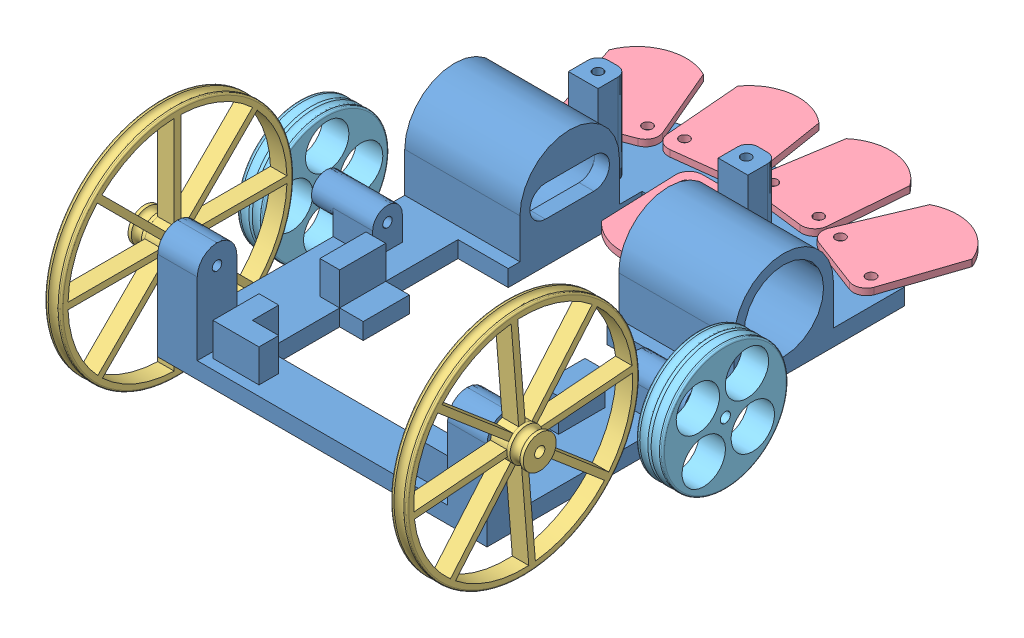
SolidWorks assembly LFR2, configuration Default. Lengths in mm.
Overall size (129.2 79.16 191.87).
11 component instances, 5 part files, 25 mates.
Components (placement in the parent):
- BODY3-1: BODY3 [Default] at origin size (113.2 33 138.84)
- BALL-1: BALL [Default] at (0 4.6 -27.733) x (1 0 0) z (0 0 -1) size (10 10 10)
- INTERMEDIATE65mm-1: INTERMEDIATE65mm [Default] at (50 27 94) x (0 0.080694 -0.996739) z (1 0 0) size (70.5 70.5 10)
- SENSOR-1: SENSOR [Default] at (-0.2782 5 -19.6543) size (24 2 32.42)
- SENSOR-2: SENSOR [Default] at (-36.4731 5 -24.2592) x (-0.934298 0 0.356493) z (-0.356493 0 -0.934298) size (24 2 32.42)
- SENSOR-3: SENSOR [Default] at (36.2225 5 -24.3544) x (-0.935229 0 -0.354044) z (0.354044 0 -0.935229) size (24 2 32.42)
- SENSOR-4: SENSOR [Default] at (12.3119 5 -30.2377) x (-0.992733 0 -0.120338) z (0.120338 0 -0.992733) size (24 2 32.42)
- SENSOR-5: SENSOR [Default] at (-12.3119 5 -30.2377) x (-0.992733 0 0.120338) z (-0.120338 0 -0.992733) size (24 2 32.42)
- INTERMEDIATE65mm-3: INTERMEDIATE65mm [Default] at (-50 27 94) x (0 0 1) z (-1 0 0) size (70.5 70.5 10)
- WHEEL-1: WHEEL [Default] at (-64.6 12.5 42.2315) x (0 -0.027962 -0.999609) z (1 0 0) size (38 38 8)
- WHEEL-2: WHEEL [Default] at (64.6 12.5 42.2315) x (0 0.618239 0.78599) z (-1 0 0) size (38 38 8)
Mates (geometry in assembly coordinates):
- Coincident1: coincident anti-aligned: plane of BODY3-1 through (0 5 71.3298) normal (0 1 0); plane of SENSOR-4 through (20.2538 5 -29.275) normal (0 -1 0)
- Coincident2: coincident anti-aligned: plane of BODY3-1 through (0 5 71.3298) normal (0 1 0); plane of SENSOR-5 through (-4.37 5 -31.2004) normal (0 -1 0)
- Coincident3: coincident anti-aligned: plane of BODY3-1 through (0 5 71.3298) normal (0 1 0); plane of SENSOR-1 through (-8.2782 5 -19.6543) normal (0 -1 0)
- Coincident4: coincident anti-aligned: plane of BODY3-1 through (0 5 71.3298) normal (0 1 0); plane of SENSOR-3 through (43.7044 5 -21.5221) normal (0 -1 0)
- Coincident5: coincident anti-aligned: plane of BODY3-1 through (0 5 71.3298) normal (0 1 0); plane of SENSOR-2 through (-28.9987 5 -27.1111) normal (0 -1 0)
- Concentric1: concentric anti-aligned: cylinder of BODY3-1 through (-44.3325 -0.001 -22.4163) axis (0 1 0) radius 1.5; cylinder of SENSOR-2 through (-44.3325 7 -22.4163) axis (0 -1 0) radius 1.5
- Concentric2: concentric anti-aligned: cylinder of BODY3-1 through (-29.3837 -0.001 -28.1202) axis (0 1 0) radius 1.5; cylinder of SENSOR-2 through (-29.3837 7 -28.1202) axis (0 -1 0) radius 1.5
- Concentric3: concentric anti-aligned: cylinder of BODY3-1 through (-20.3837 -0.001 -30.3471) axis (0 1 0) radius 1.5; cylinder of SENSOR-5 through (-20.3837 7 -30.3471) axis (0 -1 0) radius 1.5
- Concentric4: concentric anti-aligned: cylinder of BODY3-1 through (-4.5 -0.001 -32.2726) axis (0 1 0) radius 1.5; cylinder of SENSOR-5 through (-4.5 7 -32.2726) axis (0 -1 0) radius 1.5
- Concentric5: concentric anti-aligned: cylinder of BODY3-1 through (4.5 -0.001 -32.2726) axis (0 1 0) radius 1.5; cylinder of SENSOR-4 through (4.5 7 -32.2726) axis (0 -1 0) radius 1.5
- Concentric6: concentric anti-aligned: cylinder of BODY3-1 through (20.3837 -0.001 -30.3471) axis (0 1 0) radius 1.5; cylinder of SENSOR-4 through (20.3837 7 -30.3471) axis (0 -1 0) radius 1.5
- Concentric7: concentric anti-aligned: cylinder of BODY3-1 through (29.1231 -0.001 -28.1968) axis (0 1 0) radius 1.5; cylinder of SENSOR-3 through (29.1231 7 -28.1968) axis (0 -1 0) radius 1.5
- Concentric8: concentric anti-aligned: cylinder of BODY3-1 through (44.0867 -0.001 -22.5321) axis (0 1 0) radius 1.5; cylinder of SENSOR-3 through (44.0867 7 -22.5321) axis (0 -1 0) radius 1.5
- Concentric9: concentric anti-aligned: cylinder of BODY3-1 through (-8.2782 -5 -18.5743) axis (0 1 0) radius 1.5; cylinder of SENSOR-1 through (-8.2782 7 -18.5743) axis (0 -1 0) radius 1.5
- Concentric10: concentric anti-aligned: cylinder of BODY3-1 through (7.7218 -5 -18.5743) axis (0 1 0) radius 1.5; cylinder of SENSOR-1 through (7.7218 7 -18.5743) axis (0 -1 0) radius 1.5
- Concentric12: concentric aligned: cylinder of BODY3-1 through (0 0 -27.733) axis (0 1 0) radius 2.5; cylinder of BALL-1 through (0 -5.4 -27.733) axis (0 1 0) radius 2.5
- Coincident7: coincident anti-aligned: plane of BODY3-1 through (0 0 71.3298) normal (0 -1 0); plane of BALL-1 through (0 0 -27.733) normal (0 1 0)
- Concentric13: concentric anti-aligned: cylinder of BODY3-1 through (38 27 94) axis (1 0 0) radius 1.45; cylinder of INTERMEDIATE65mm-1 through (60 27 94) axis (-1 0 0) radius 1.55
- Coincident8: coincident anti-aligned: plane of BODY3-1 through (50 5 -26.8369) normal (1 0 0); plane of INTERMEDIATE65mm-1 through (50 62.135 96.8445) normal (-1 0 0)
- Concentric14: concentric anti-aligned: cylinder of BODY3-1 through (-38 27 94) axis (-1 0 0) radius 1.45; cylinder of INTERMEDIATE65mm-3 through (-60 27 94) axis (1 0 0) radius 1.55
- Coincident9: coincident anti-aligned: plane of BODY3-1 through (-50 5 35) normal (-1 0 0); plane of INTERMEDIATE65mm-3 through (-50 62.25 94) normal (1 0 0)
- Concentric15: concentric anti-aligned: cylinder of BODY3-1 through (-38 12.5 42.2315) axis (-1 0 0) radius 1.45; cylinder of WHEEL-1 through (-64.6 12.5 42.2315) axis (1 0 0) radius 1.55
- Concentric17: concentric anti-aligned: cylinder of BODY3-1 through (38 12.5 42.2315) axis (1 0 0) radius 1.45; cylinder of WHEEL-2 through (64.6 12.5 42.2315) axis (-1 0 0) radius 1.55
- Coincident12: coincident anti-aligned: plane of BODY3-1 through (56.6 12.5 42.2315) normal (1 0 0); plane of WHEEL-2 through (56.6 12.5 42.2315) normal (-1 0 0)
- Coincident13: coincident anti-aligned: plane of BODY3-1 through (-56.6 12.5 42.2315) normal (-1 0 0); plane of WHEEL-1 through (-56.6 12.5 42.2315) normal (1 0 0)
